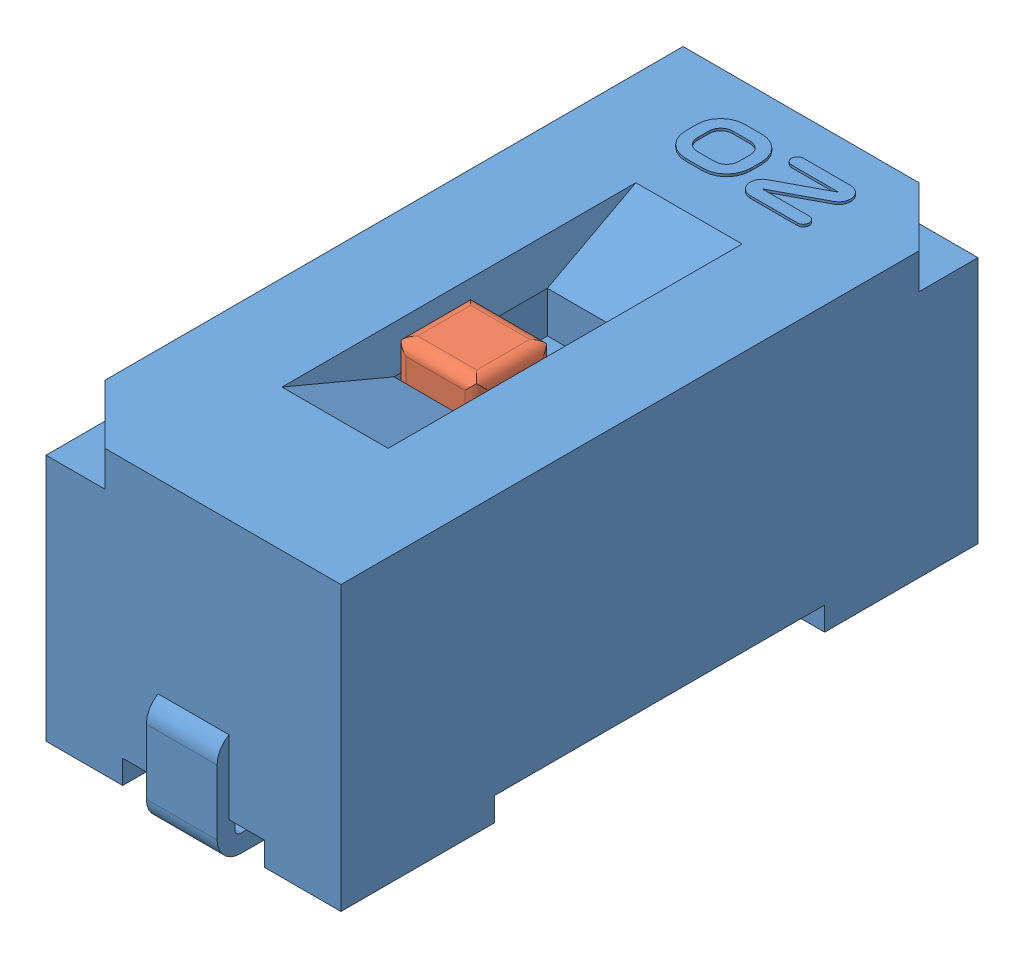
SolidWorks assembly CHS-01TA, configuration Default. Lengths in mm.
Overall size (2.5 2.52 5.6).
3 component instances, 2 part files, 0 mates.
Components (placement in the parent):
- CHS-01TA.stp-1: CHS-01TA.stp [Default] at origin size (2.5 2.52 5.6)
  - _CHS-01-J-body.stp-1: _CHS-01-J-body.stp [Default] at origin size (2.5 2.52 5.6)
  - _CHS-slider.stp-1: _CHS-slider.stp [Default] at (0 1.75 0) size (0.7 0.65 0.65)
